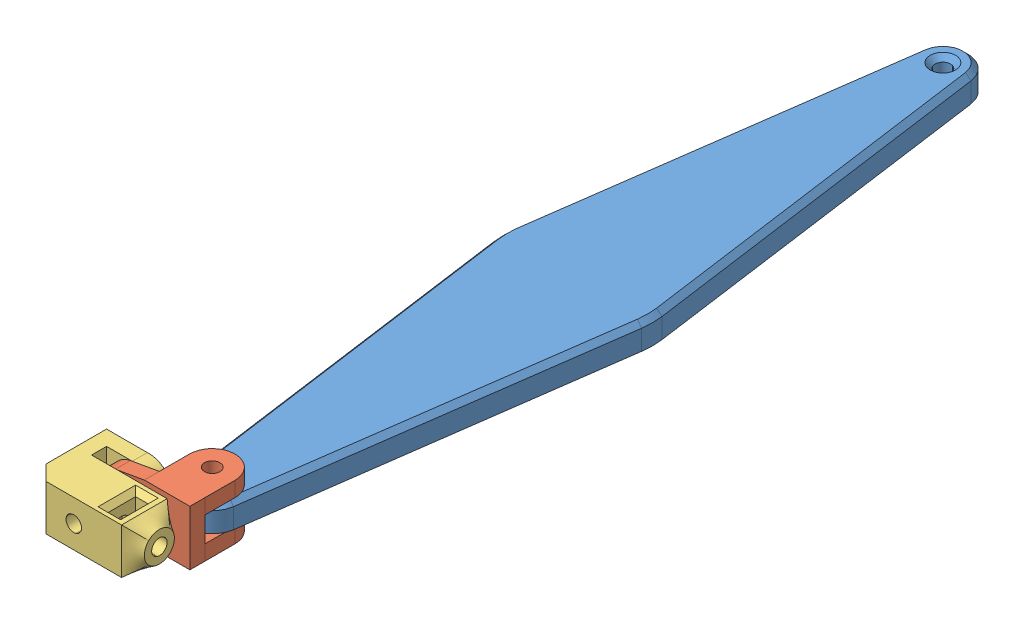
SolidWorks assembly Assem1, configuration Default. Lengths in mm.
Overall size (33.11 11 169.11).
3 component instances, 3 part files, 5 mates.
Components (placement in the parent):
- differentialBar-1: differentialBar [Default] at (-75.6508 -1.1329 -7.7684) x (1 0 0) z (0 1 0) size (30 156 5)
- differentialHinge-1: differentialHinge [Default] at (94.3556 -1.1329 -7.6582) x (-0.999999 0 -0.001295) z (0 -1 0) size (18.65 13.57 11)
- rodHinge-diff-1: rodHinge-diff [Default] at (94.3556 -1.1329 6.2375) size (21.11 9.1 15.1)
Mates (geometry in assembly coordinates):
- Coincident2: coincident anti-aligned: plane of differentialBar-1 through (-75.6508 -1.1329 -7.7684) normal (0 -1 0); plane of differentialHinge-1 through (94.3556 -1.1329 -7.6582) normal (0 1 0)
- Concentric2: concentric anti-aligned: cylinder of differentialBar-1 through (9.3492 -1.1339 -2.7684) axis (0 1 0) radius 1.55; cylinder of differentialHinge-1 through (9.3492 6.8671 -2.7684) axis (0 -1 0) radius 1.55
- Parallel1: parallel aligned: plane of differentialBar-1; plane of differentialHinge-1 through (94.3556 -1.1329 6.2375) normal (0 0 1)
- Concentric3: concentric: cylinder of differentialHinge-1 through (-0.2086 1.3671 6.2375) axis (0 0 -1) radius 1.55; cylinder of rodHinge-diff-1 through (-0.2086 1.3671 0.2375) axis (0 0 1) radius 1.55
- Coincident7: coincident anti-aligned: plane of differentialHinge-1 through (94.3556 -1.1329 3.2375) normal (0 0 -1); plane of rodHinge-diff-1 through (94.3556 -1.1329 3.2375) normal (0 0 1)
